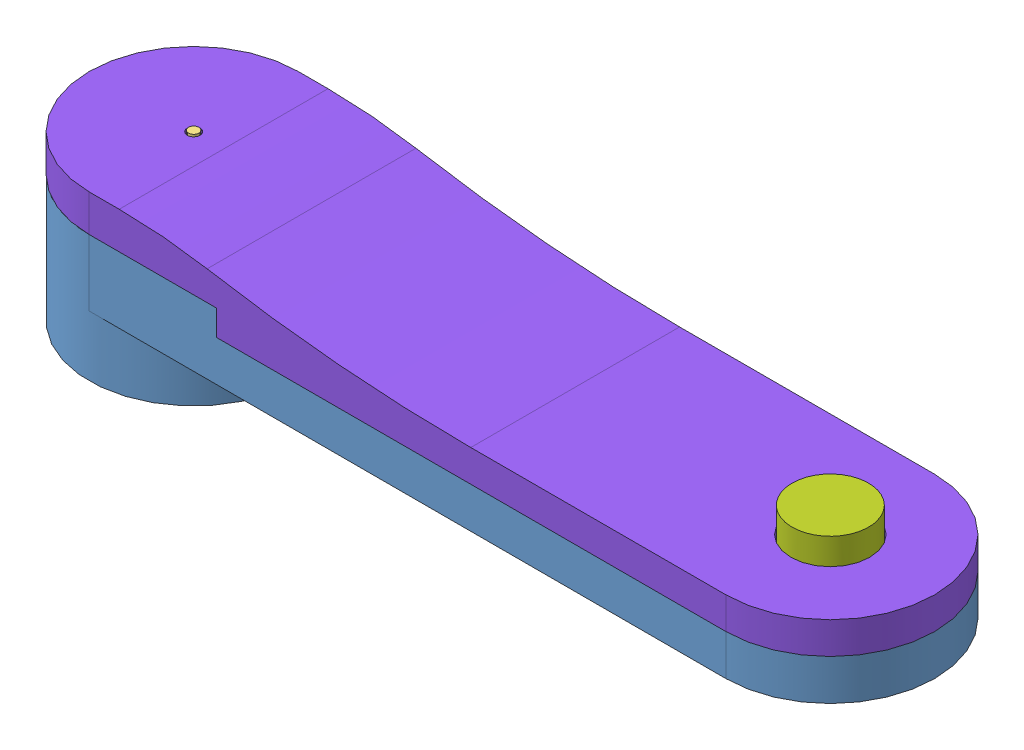
SolidWorks assembly upperlimbaseemblyv2, configuration Default. Lengths in mm.
Overall size (332 64.8 82).
8 component instances, 8 part files, 18 mates.
Components (placement in the parent):
- upper limb v2-1: upper limb v2 [Default] at (4.749 186.9154 245.8828) size (332 49.8 82)
- MAD5008IPE-1: MAD5008IPE [Default] at (4.749 162.1154 245.8828) size (56 29.3 56)
- GT2 10T-1: GT2 10T [Default] at (4.749 188.5622 245.8828) size (34 34 34)
- encoderholder-1: encoderholder [Default] at (19.749 201.9154 245.8828) x (0 0 -1) z (1 0 0) size (68 5 47.5)
- encoder-1: encoder [Default] at (4.749 210.6854 245.8828) x (-0.020235 0 -0.999795) z (0 1 0) size (28.79 43.54 9.21)
- W_61706_2RZ-1: W_61706_2RZ [Default] at (254.749 186.9154 245.8828) x (0 -1 0) z (0 0 1) size (4 46.12 46.12)
- GT2_80T-1: GT2_80T [Default] at (254.749 182.4154 245.8828) x (0.982909 0 -0.18409) z (0 1 0) size (55 55 47.5)
- upper limb cover v2-1: upper limb cover v2 [Default] at (4.749 196.9154 245.8828) size (332 24.5 82)
Mates (geometry in assembly coordinates):
- Concentric1: concentric anti-aligned: cylinder of upper limb v2-1 through (4.749 157.1154 260.8828) axis (0 1 0) radius 1.5; cylinder of MAD5008IPE-1 through (4.749 165.1154 260.8828) axis (0 -1 0) radius 1.5
- Concentric2: concentric aligned: cylinder of upper limb v2-1 through (4.749 206.9154 245.8828) axis (0 -1 0) radius 29; cylinder of MAD5008IPE-1 through (4.749 187.9154 245.8828) axis (0 -1 0) radius 28
- Coincident1: coincident anti-aligned: plane of upper limb v2-1 through (4.749 162.1154 245.8828) normal (0 1 0); plane of MAD5008IPE-1 through (4.749 162.1154 245.8828) normal (0 -1 0)
- Concentric3: concentric aligned: cylinder of MAD5008IPE-1 through (12.249 184.9154 245.8828) axis (0 1 0) radius 1.5; cylinder of GT2 10T-1 through (12.249 186.9154 245.8828) axis (0 1 0) radius 1.5
- Concentric4: concentric aligned: cylinder of MAD5008IPE-1 through (-2.751 184.9154 245.8828) axis (0 1 0) radius 1.5; cylinder of GT2 10T-1 through (-2.751 186.9154 245.8828) axis (0 1 0) radius 1.5
- Coincident2: coincident anti-aligned: plane of MAD5008IPE-1 through (4.749 187.9154 245.8828) normal (0 1 0); plane of GT2 10T-1 through (-12.251 187.9154 245.8828) normal (0 -1 0)
- Coincident3: coincident anti-aligned: plane of upper limb v2-1 through (4.749 206.9154 279.8828) normal (0 0 -1); plane of encoderholder-1 through (34.749 206.9154 279.8828) normal (0 0 1)
- Coincident4: coincident anti-aligned: plane of upper limb v2-1 through (34.749 206.9154 176.469) normal (-1 0 0); plane of encoderholder-1 through (34.749 206.9154 279.8828) normal (1 0 0)
- Coincident5: coincident anti-aligned: plane of upper limb v2-1 through (4.749 201.9154 176.469) normal (0 1 0); plane of encoderholder-1 through (19.749 201.9154 245.8828) normal (0 -1 0)
- Concentric5: concentric anti-aligned: cylinder of GT2 10T-1 through (4.749 205.9154 245.8828) axis (0 -1 0) radius 2; cylinder of encoder-1 through (4.749 211.0386 245.8828) axis (0 1 0) radius 2
- Coincident6: coincident anti-aligned: plane of encoderholder-1 through (19.749 206.9154 245.8828) normal (0 1 0); plane of encoder-1 through (33.0817 206.9154 259.6996) normal (0 -1 0)
- Concentric6: concentric anti-aligned: cylinder of upper limb v2-1 through (254.749 182.9154 245.8828) axis (0 1 0) radius 18.5; cylinder of W_61706_2RZ-1 through (254.749 136.9154 245.8828) axis (0 -1 0) radius 18.5
- Coincident9: coincident anti-aligned: plane of upper limb v2-1 through (254.749 182.9154 245.8828) normal (0 1 0); plane of W_61706_2RZ-1 through (269.949 182.9154 245.8828) normal (0 -1 0)
- Concentric7: concentric anti-aligned: cylinder of W_61706_2RZ-1 through (254.749 136.9154 245.8828) axis (0 -1 0) radius 15; cylinder of GT2_80T-1 through (254.749 171.9154 245.8828) axis (0 1 0) radius 15
- Coincident10: coincident anti-aligned: plane of upper limb v2-1 through (4.749 186.9154 245.8828) normal (0 1 0); plane of GT2_80T-1 through (254.749 186.9154 245.8828) normal (0 -1 0)
- Coincident11: coincident anti-aligned: plane of upper limb v2-1 through (254.749 196.9154 245.8828) normal (0 1 0); plane of upper limb cover v2-1 through (4.749 196.9154 245.8828) normal (0 -1 0)
- Coincident12: coincident anti-aligned: plane of upper limb v2-1 through (54.749 196.9154 204.8828) normal (1 0 0); plane of upper limb cover v2-1 through (54.749 196.9154 245.8828) normal (-1 0 0)
- Coincident13: coincident aligned: plane of upper limb v2-1 through (4.749 206.9154 216.8828) normal (0 0 1); plane of upper limb cover v2-1 through (4.749 204.4154 216.8828) normal (0 0 1)
